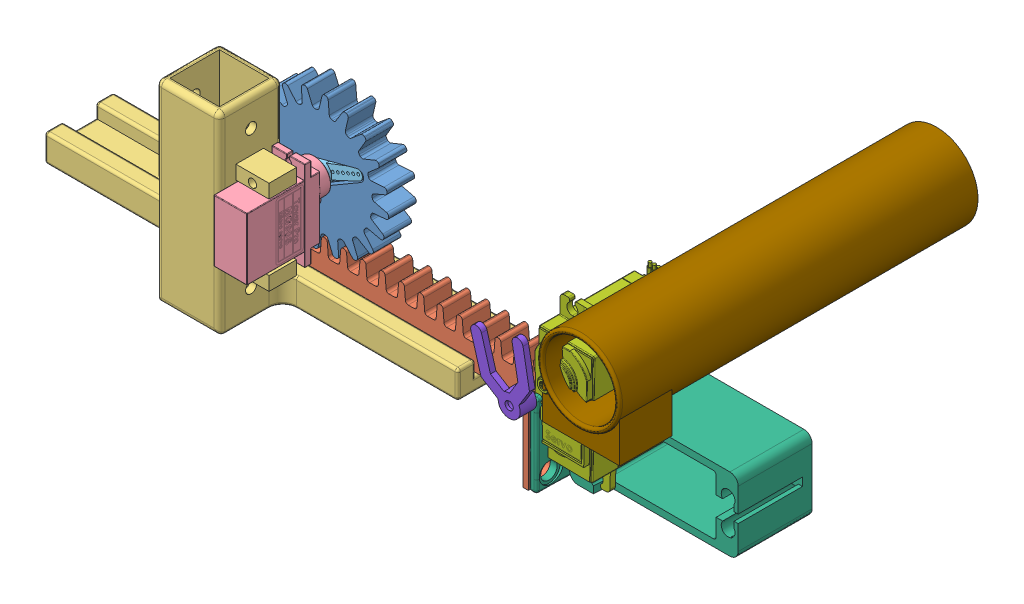
SolidWorks assembly Rack-Pinion-Assembly, configuration Default. Lengths in mm.
Overall size (250.08 74.71 141.93).
11 component instances, 9 part files, 16 mates.
Components (placement in the parent):
- Pinion-1: Pinion [Default] at (0 0 -10) x (-0.384217 0.923243 0) z (0 0 1) size (49.45 49.45 10)
- Rack-1: Rack [Default] at (19.0751 -34.8811 -5) size (151 30 50)
- Rack Mount-1: Rack Mount [Default] at (-17.5 -39.8811 -5) x (-1 0 0) z (0 0 -1) size (150 70 48)
- MG90 servo-1: MG90 servo [Default] at (0 -5.25 11.5) x (0 1 0) z (0 0 1) size (32.5 12 34)
- MG90 horn-1: MG90 horn [По умолчанию] at (0 0 -2.5) x (-0.921063 -0.389414 0) z (0 0 1) size (32 7.5 5)
- Support+Dropper-1: Support+Dropper [Défaut] at (125.1127 -18.3733 79.2259) x (0 1 0) z (0 0 -1) size (69.63 72.61 141.93)
  - Servo Mount (Standing)-1: Servo Mount (Standing) [Default] at (-9.0078 4.4624 68.2259) size (30 62 50)
  - Dropper-1: Dropper [Défaut] at (19.2549 9.208 -9.925) x (0 1 0) z (0.010928 0 0.99994) size (34.82 67.09 56.96)
    - MG995 (1)-1: MG995 (1) [Défaut] at (-29.3153 14.7553 109.1659) x (0.016609 -0.999802 0.010927) z (0 -0.010928 -0.99994) size (55.5 20 44.5)
    - Pièce2-1: Pièce2 [Défaut] at (-29.1492 4.2032 58.5817) x (0.526861 -0.849901 0.009289) z (0 -0.010928 -0.99994) size (25.29 25.29 6)
  - Tube-1: Tube [Défaut] at (24.2422 -6.385 54.2537) x (0 1 0) z (0 0 1) size (30 35 130)
Mates (geometry in assembly coordinates):
- Coincident10: coincident aligned: plane of Rack-1 through (-55.4249 -19.8811 0) normal (0 0 1)
- Coincident11: coincident aligned: plane of Pinion-1 through (0 0 0) normal (0 0 1)
- Concentric1: concentric aligned: circle of pinion-1
- Distance2: distance = 26 mm: line of assembly; line of assembly; line of Rack-1 through (88.5751 -34.8811 -10) axis (-1 0 0)
- RackPinionMate4: rack pinion = 44 mm: line of Rack-1 through (88.5751 -34.8811 -10) axis (-1 0 0); circle of pinion-1
- Coincident12: coincident anti-aligned: plane of Rack-1 through (19.0751 -34.8811 -5) normal (0 -1 0); plane of rack holder-1 through (-17.5 -34.8811 -5) normal (0 1 0)
- Distance3: distance = 1 mm anti-aligned: plane of Rack-1 through (-55.4249 -19.8811 -10) normal (0 0 -1); plane of rack holder-1 through (57.5 -34.8811 -11) normal (0 0 1)
- Concentric2: concentric aligned: circle of pinion-1; circle of MG90s_servo-1
- Coincident16: coincident anti-aligned: plane of rack holder-1 through (-6 30.1189 30.5) normal (1 0 0); plane of MG90s_servo-1 through (-6 -16.5 32.5) normal (-1 0 0)
- Lock1: lock: unknown of Pinion-1; unknown of MG90 horn-1
- Concentric3: concentric anti-aligned: circle of pinion-1; circle of Microservo horn-1
- Coincident19: coincident anti-aligned: plane of MG90s_servo-1 through (0 0 -1.5) normal (0 0 -1); plane of MG90 horn-1 through (0 0 -1.5) normal (0 0 1)
- Parallèle1: parallel aligned: plane of Rack Mount-1 through (-17.5 -29.8811 -17.5) normal (0 0 -1); plane of Support+Dropper-1/Servo Mount (Standing)-1 through (95.5751 -42.3811 -30) normal (0 0 -1)
- Coïncidente1: coincident anti-aligned: plane of Rack-1 through (95.5751 -34.8811 -5) normal (1 0 0); plane of Support+Dropper-1/Servo Mount (Standing)-1 through (95.5751 -27.3811 11) normal (-1 0 0)
- Coïncidente2: coincident aligned: plane of Rack-1 through (95.5751 -42.3811 20) normal (0 -1 0); plane of Support+Dropper-1/Servo Mount (Standing)-1 through (95.5751 -42.3811 -30) normal (0 -1 0)
- Coïncidente3: coincident aligned: plane of Rack-1 through (95.5751 -42.3811 -30) normal (0 0 -1); plane of Support+Dropper-1/Servo Mount (Standing)-1 through (95.5751 -42.3811 -30) normal (0 0 -1)
